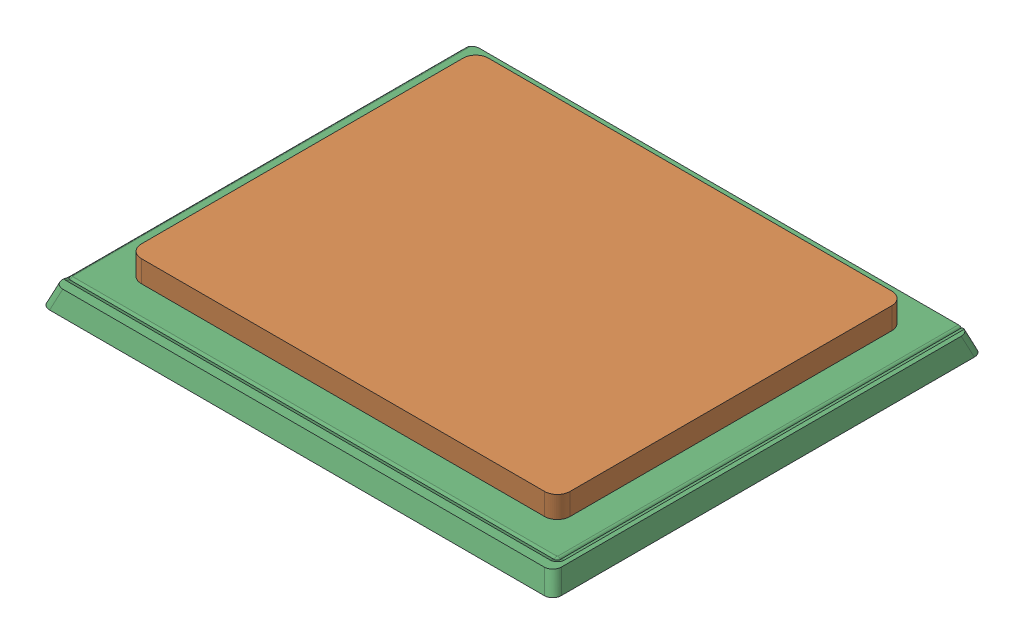
SolidWorks assembly Newlens, configuration 默认. Lengths in mm.
Overall size (28.33 3.2 23.83).
2 component instances, 2 part files, 0 mates.
Components (placement in the parent):
- 611Lens-1: 611Lens [默认] at (-93.8373 43.1309 1.5226) x (1 0 0) z (0 -1 0) size (24.45 17.04 1)
- 611Down-1: 611Down [默认] at (-92.713 25.1309 0) size (28.33 2.44 23.83)
